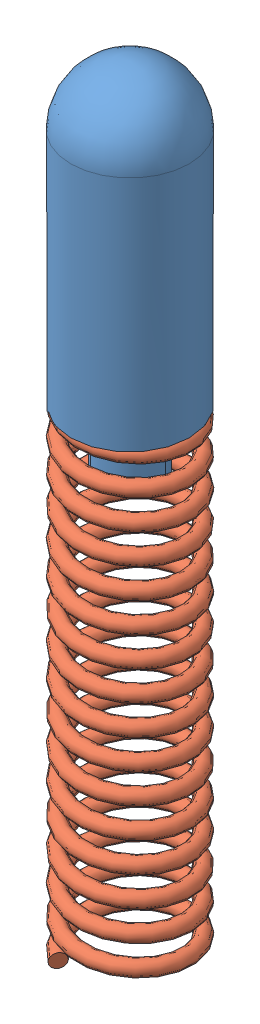
SolidWorks assembly Assem6, configuration Default. Lengths in mm.
Overall size (12.86 52.5 12.73).
2 component instances, 2 part files, 2 mates.
Components (placement in the parent):
- Part132132-1: Part132132 [Default] at (3.7101 -7.0738 2.848) size (8 24 8)
- Part9213-1: Part9213 [Default] at (3.7101 -3.0738 2.848) x (-0.837169 0 -0.546944) z (-0.546944 0 0.837169) size (9.46 33 9.03)
Mates (geometry in assembly coordinates):
- Concentric1: concentric anti-aligned: circle of Part132132-1; circle of Part9213-1
- Coincident1: coincident aligned: plane of Part132132-1 through (5.7101 -3.0738 2.848) normal (0 -1 0); circle of Part9213-1
